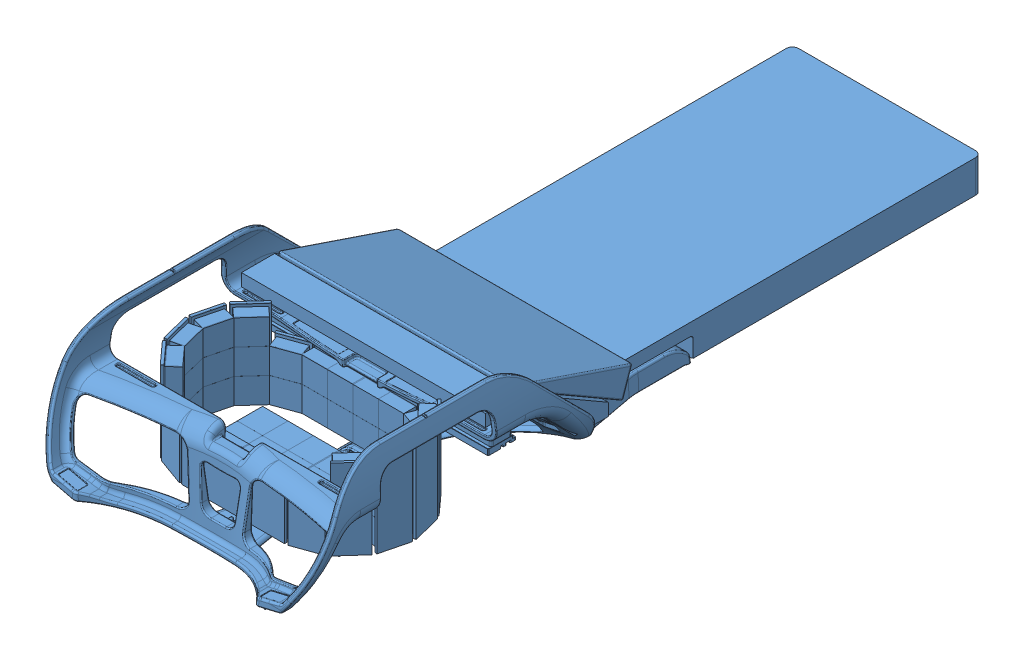
SolidWorks assembly Assem1, configuration Default. Lengths in mm.
Overall size (567.96 474.97 2009.25).
2 component instances, 2 part files, 0 mates.
Components (placement in the parent):
- Prone3-1: Prone3 [Default] at (-100.1047 -108.125 -560.9144) size (470.18 474.97 2009.25)
- PETMR_SentinelleDetector_bedpart-1: PETMR_SentinelleDetector_bedpart [Default] at (-81.5113 -11.465 109.0076) size (567.96 277.55 1480.39)
